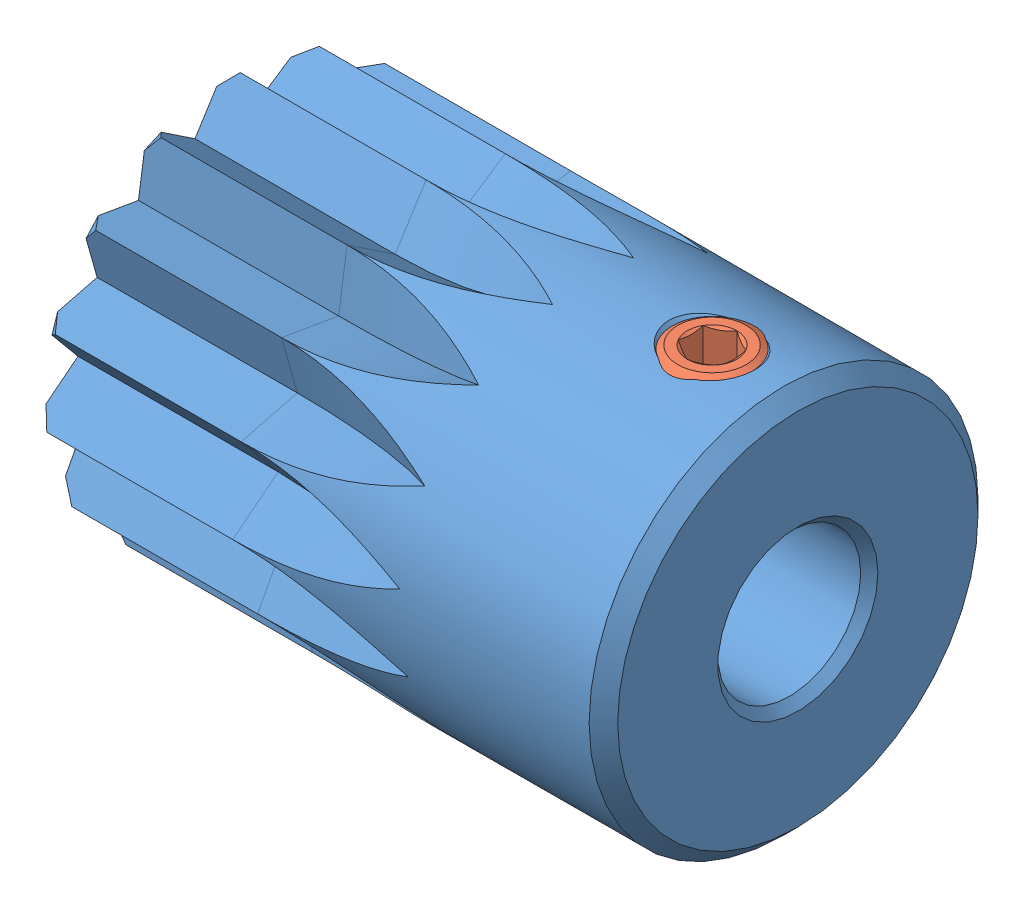
SolidWorks assembly GEABS0_8_15_7_K_5, configuration Default. Lengths in mm.
Overall size (20 13.68 13.6).
2 component instances, 2 part files, 0 mates.
Components (placement in the parent):
- GEABS0_8_15_7_5_1-1: GEABS0_8_15_7_5_1 [Default] x (0 0 -1) z (1 0 0) size (13.6 13.6 20)
- Hexagon_socket_set_screw_with_flat_point_DIN_913___M3x4-1: Hexagon_socket_set_screw_with_flat_point_DIN_913___M3x4 [Default] at (17 6.8 0) x (0 -1 0) z (0 0 1) size (4.08 3 3)
